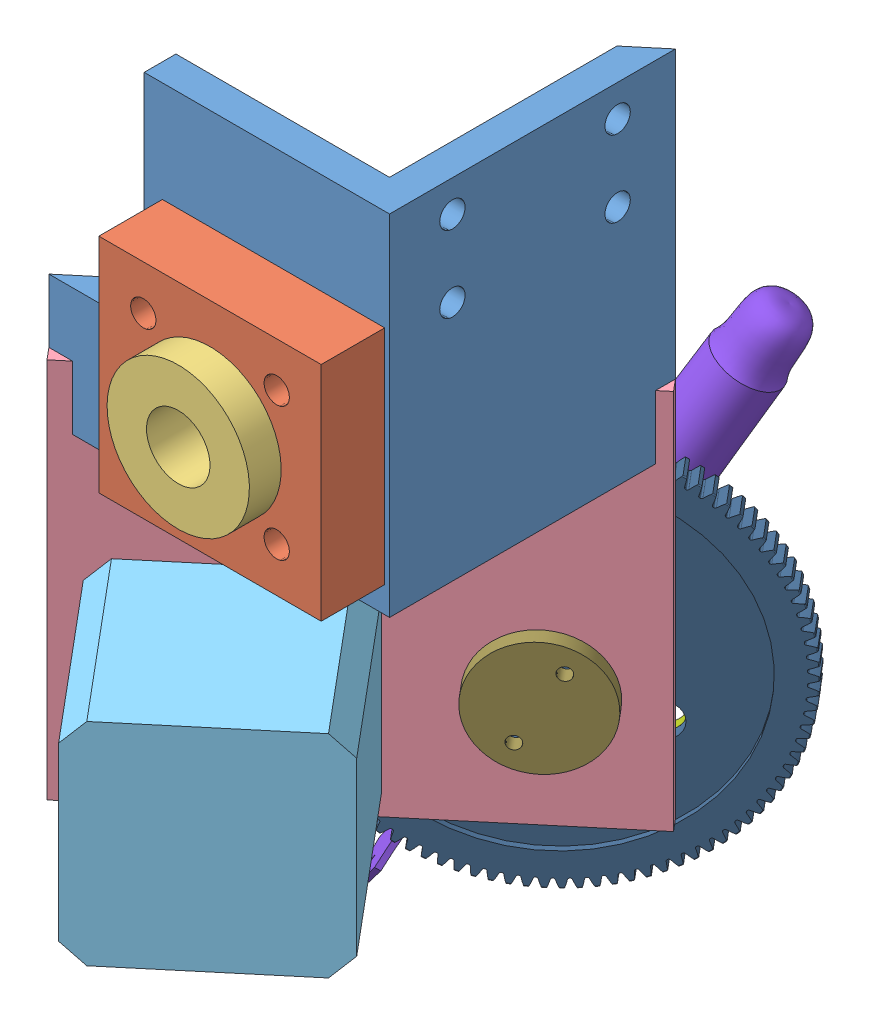
SolidWorks assembly Print head assembly, configuration Default. Lengths in mm.
Overall size (104.85 165.22 120.96).
13 component instances, 13 part files, 30 mates.
Components (placement in the parent):
- L shape-1: L shape [Default] at (-44.6957 -20.7444 37.6787) size (68.1 69.85 57.14)
- Print head nut plate-1: Print head nut plate [Default] at (0.2155 6.6876 37.6787) size (44.45 44.45 12.7)
- ACME nut fast travel-1: ACME nut fast travel [Default] at (0.2155 6.6876 56.7287) x (0.98588 -0.167452 0) z (0.167452 0.98588 0) size (28.45 19.05 28.45)
- Mechanical plate-1: Mechanical plate [Default] at (-44.6957 -84.2444 37.6787) x (0.766044 0 -0.642788) z (0.642788 0 0.766044) size (88.9 76.2 3.05)
- Stepper Pololu-2: Stepper Pololu [Default] at (-11.6642 -40.4944 68.768) x (0.766044 0 -0.642788) z (0 1 0) size (42.3 64 42.3)
- Gear small-1: Gear small [Default] at (-28.8514 -61.6444 15.3816) x (-0.642788 0 -0.766044) z (-0.711393 0.370938 0.59693) size (12.72 12.73 12.52)
- P clamp-1: P clamp [Default] at (21.3044 -75.0207 -28.2493) x (0.660571 -0.506373 -0.554285) z (0.387904 0.862315 -0.32549) size (35.56 20.32 16.76)
- Pen-1: Pen [Default] at (18.3601 -16.8874 -39.0416) x (0.387904 0.862315 -0.32549) z (0.660571 -0.506373 -0.554285) size (122.97 14 14)
- Spacer large-1: Spacer large [Default] at (9.0483 -61.6444 -7.4178) x (0.586824 0.642788 -0.492404) z (-0.492404 0.766044 0.413176) size (27.94 5.71 27.94)
- Gear large-2: Gear large [Default] at (4.6156 -61.6444 -12.7005) x (0.642788 0 0.766044) z (0.660571 -0.506373 -0.554285) size (12.71 77.81 77.81)
- Spacer small-1: Spacer small [Default] at (-24.4186 -61.6444 20.6643) x (0.586824 0.642788 -0.492404) z (-0.492404 0.766044 0.413176) size (12.7 4.52 12.7)
- Gear back plate-1: Gear back plate [Default] at (13.2116 -61.6444 -2.4561) x (-0.660571 0.506373 0.554285) z (-0.387904 -0.862315 0.32549) size (22.86 3.05 22.86)
- Set screw-1: Set screw [Default] at (-31.5169 -56.964 9.2964) x (0.927762 -0.203583 0.312748) z (-0.284155 -0.928658 0.238434) size (2.54 2.54 2.54)
Mates (geometry in assembly coordinates):
- Concentric1: concentric aligned: cylinder of L shape-1 through (-13.1195 20.0226 37.6787) axis (0 0 -1) radius 2.54; cylinder of Print head nut plate-1 through (-13.1195 20.0226 50.3787) axis (0 0 -1) radius 2.54
- Concentric2: concentric aligned: cylinder of L shape-1 through (13.5505 20.0226 37.6787) axis (0 0 -1) radius 2.54; cylinder of Print head nut plate-1 through (13.5505 20.0226 50.3787) axis (0 0 -1) radius 2.54
- Coincident1: coincident anti-aligned: plane of L shape-1 through (-44.6957 49.1056 37.6787) normal (0 0 1); plane of Print head nut plate-1 through (0.2155 6.6876 37.6787) normal (0 0 -1)
- Concentric3: concentric aligned: cylinder of Print head nut plate-1 through (0.2155 6.6876 50.3787) axis (0 0 -1) radius 11.8999; cylinder of ACME nut fast travel-1 through (0.2155 6.6876 56.7287) axis (0 0 -1) radius 11.8999
- Coincident2: coincident anti-aligned: plane of Print head nut plate-1 through (0.2155 6.6876 50.3787) normal (0 0 1); plane of ACME nut fast travel-1 through (14.2386 4.3058 50.3787) normal (0 0 -1)
- Concentric4: concentric aligned: circle of Mechanical plate-1; circle of Stepper Pololu-2
- Concentric5: concentric aligned: cylinder of Mechanical plate-1 through (-10.5857 -77.1444 13.036) axis (-0.642788 0 -0.766044) radius 2.54; cylinder of Stepper Pololu-2 through (-6.0862 -77.1444 18.3983) axis (-0.642788 0 -0.766044) radius 1.5
- Coincident7: coincident anti-aligned: plane of Mechanical plate-1 through (-42.7365 -84.2444 40.0137) normal (0.642788 0 0.766044); plane of Stepper Pololu-2 through (-14.0329 -61.6444 15.9285) normal (-0.642788 0 -0.766044)
- Coincident9: coincident anti-aligned: plane of L shape-1 through (-42.7365 -20.7444 40.0137) normal (-0.642788 0 -0.766044); plane of Mechanical plate-1 through (-42.7365 -84.2444 40.0137) normal (0.642788 0 0.766044)
- Coincident10: coincident anti-aligned: plane of L shape-1 through (25.3649 -8.0444 -17.1302) normal (0 -1 0); plane of Mechanical plate-1 through (-42.7365 -8.0444 40.0137) normal (0 1 0)
- Coincident11: coincident aligned: line of L shape-1 through (-44.6957 4.6556 37.6787) axis (0 -1 0); line of Mechanical plate-1 through (-44.6957 -8.0444 37.6787) axis (0 -1 0)
- Concentric7: concentric aligned: circle of Stepper Pololu-2; circle of Gear small-1
- Concentric12: concentric anti-aligned: circle of P clamp-1; circle of Pen-1
- Coincident18: coincident aligned: plane of P clamp-1 through (21.3044 -75.0207 -28.2493) normal (0.387904 0.862315 -0.32549); plane of Pen-1
- Parallel2: parallel anti-aligned: plane of P clamp-1; plane of Pen-1 through (-22.6701 -112.3034 0.1778) normal (-0.660571 0.506373 0.554285)
- Coincident19: coincident anti-aligned: plane of Mechanical plate-1 through (-44.6957 -84.2444 37.6787) normal (-0.642788 0 -0.766044); plane of Spacer large-1 through (9.0483 -61.6444 -7.4178) normal (0.642788 0 0.766044)
- Concentric13: concentric anti-aligned: cylinder of Mechanical plate-1 through (11.0075 -61.6444 -5.0829) axis (-0.642788 0 -0.766044) radius 10.3124; cylinder of Spacer large-1 through (5.3764 -61.6444 -11.7938) axis (0.642788 0 0.766044) radius 10.3124
- Concentric14: concentric anti-aligned: cylinder of Spacer large-1 through (5.3764 -61.6444 -11.7938) axis (0.642788 0 0.766044) radius 13.97; circle of Gear large-2
- Coincident23: coincident anti-aligned: plane of Spacer large-1 through (5.3764 -61.6444 -11.7938) normal (-0.642788 0 -0.766044); plane of Gear large-2 through (5.3764 -61.6444 -11.7938) normal (0.642788 0 0.766044)
- Coincident24: coincident aligned: circle of P clamp-1; circle of Gear large-2
- Concentric15: concentric aligned: cylinder of P clamp-1 through (12.244 -68.0753 -20.6467) axis (-0.642788 0 -0.766044) radius 1.27; cylinder of Gear large-2 through (19.6417 -68.0753 -11.8305) axis (-0.642788 0 -0.766044) radius 1.27
- Concentric16: concentric anti-aligned: cylinder of Stepper Pololu-2 through (-36.6007 -61.6444 6.1462) axis (-0.642788 0 -0.766044) radius 2.5; cylinder of Spacer small-1 through (-27.3248 -61.6444 17.2008) axis (0.642788 0 0.766044) radius 2.5
- Coincident25: coincident anti-aligned: plane of Mechanical plate-1 through (-44.6957 -84.2444 37.6787) normal (-0.642788 0 -0.766044); plane of Spacer small-1 through (-24.4186 -61.6444 20.6643) normal (0.642788 0 0.766044)
- Coincident26: coincident anti-aligned: plane of Gear small-1 through (-29.1292 -67.5414 18.7149) normal (0.642788 0 0.766044); plane of Spacer small-1 through (-27.3248 -61.6444 17.2008) normal (-0.642788 0 -0.766044)
- GearMate2: gear = 12.3031 : 77.3906 mm: circle of Gear large-2; circle of Gear small-1
- Coincident27: coincident anti-aligned: cylinder of Gear large-2 through (12.3891 -55.4881 -9.0606) axis (0.642788 0 0.766044) radius 1.27; circle of Gear back plate-1
- Concentric17: concentric aligned: cylinder of Gear large-2 through (6.8504 -67.8007 -4.413) axis (0.642788 0 0.766044) radius 1.27; cylinder of Gear back plate-1 through (8.4831 -67.8007 -2.4673) axis (0.642788 0 0.766044) radius 1.27
- Coincident29: coincident anti-aligned: plane of Gear large-2 through (11.2524 -61.6444 -4.7911) normal (0.642788 0 0.766044); plane of Gear back plate-1 through (11.2524 -61.6444 -4.7911) normal (-0.642788 0 -0.766044)
- Concentric18: concentric anti-aligned: cylinder of Gear small-1 through (-31.1408 -55.7348 8.9808) axis (-0.284155 -0.928658 0.238434) radius 1.27; cylinder of Set screw-1 through (-32.2387 -59.3228 9.902) axis (0.284155 0.928658 -0.238434) radius 1.27
- Tangent1: tangent anti-aligned: cylinder of Stepper Pololu-2 through (-36.6007 -61.6444 6.1462) axis (-0.642788 0 -0.766044) radius 2.5; plane of Set screw-1 through (-32.2387 -59.3228 9.902) normal (-0.284155 -0.928658 0.238434)
